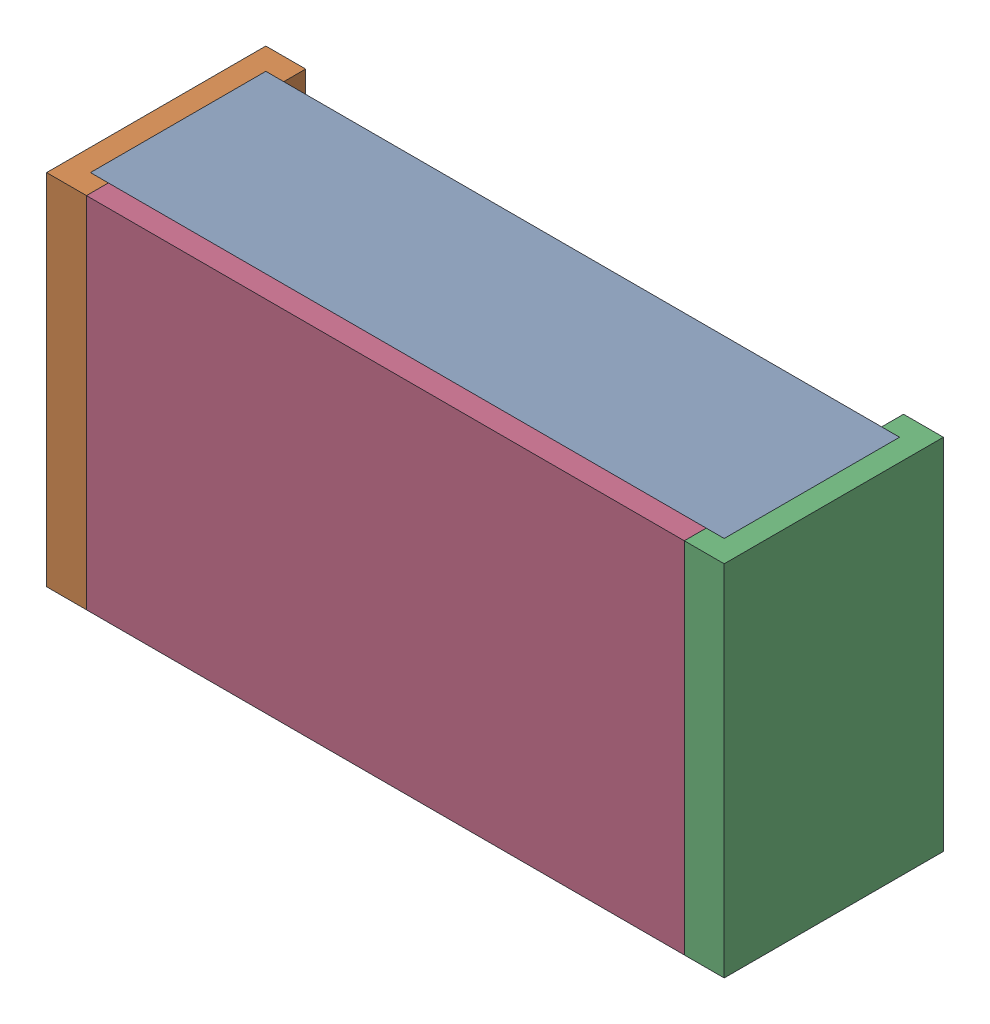
SolidWorks assembly 6019289040, configuration Default. Lengths in mm.
Overall size (1.7 0.9 0.55).
6 component instances, 3 part files, 0 mates.
Components (placement in the parent):
- Mid_Body-1: Mid_Body [Default] at (-0.85 -0.45 0) size (1.59 0.9 0.44)
- Terminal-1: Terminal [Default] at (-0.85 -0.45 0) size (0.1 0.9 0.55)
  - Open CASCADE STEP translator 6.8 15.2.1-1: Open CASCADE STEP translator 6.8 15.2.1 [Default] at origin size (0.1 0.9 0.55)
- Terminal-2: Terminal [Default] at (0.85 0.45 0) x (-1 0 0) z (0 0 1) size (0.1 0.9 0.55)
  - Open CASCADE STEP translator 6.8 15.2.1-1: Open CASCADE STEP translator 6.8 15.2.1 [Default] at origin size (0.1 0.9 0.55)
- Mark-1: Mark [Default] at (-0.75 -0.45 0.495) size (1.5 0.9 0.06)
